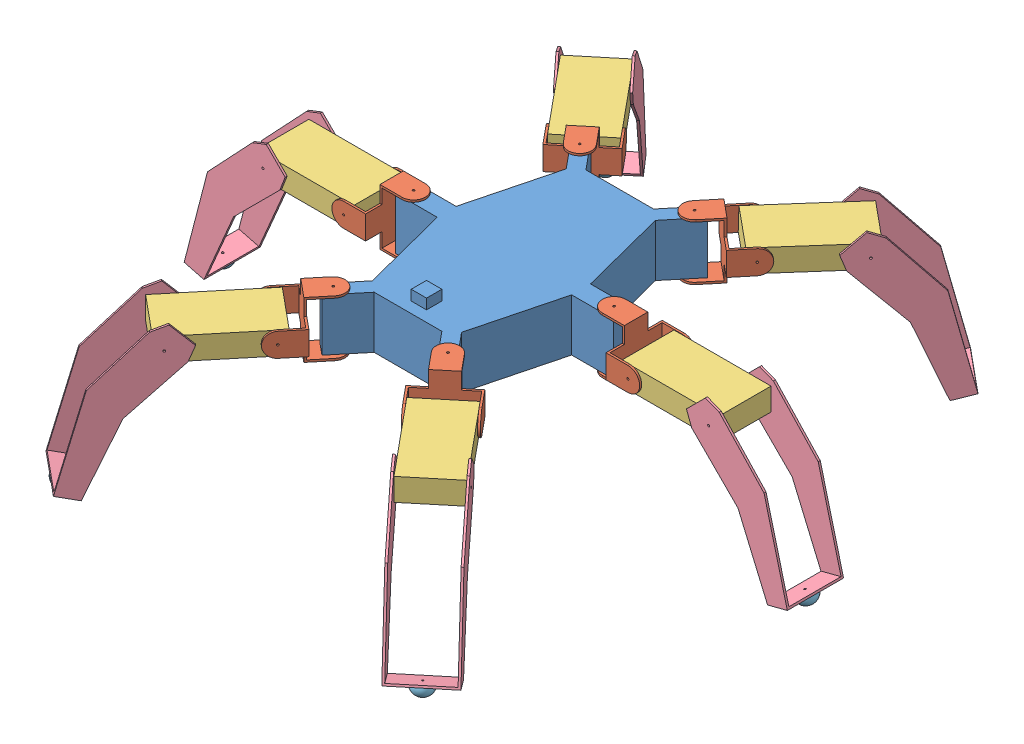
SolidWorks assembly Spider, configuration 默认. Lengths in mm.
Overall size (658.1 217.67 632.08).
25 component instances, 5 part files, 25 mates.
Components (placement in the parent):
- body-1: body [默认] at origin size (213.14 61 263.08)
- joint1-1: joint1 [默认] at (-68.5521 25.5 135.6395) x (0.770073 0 0.637956) z (-0.637956 0 0.770073) size (55 55 64)
- joint1-2: joint1 [默认] at (68.5521 25.5 135.6395) x (0.770073 0 -0.637956) z (0.637956 0 0.770073) size (55 55 64)
- joint1-3: joint1 [默认] at (117.5676 25.5 0) x (0 0 -1) z (1 0 0) size (55 55 64)
- joint1-5: joint1 [默认] at (68.5521 25.5 -135.6395) x (-0.770073 0 -0.637956) z (0.637956 0 -0.770073) size (55 55 64)
- joint1-6: joint1 [默认] at (-68.5521 25.5 -135.6395) x (-0.770073 0 0.637956) z (-0.637956 0 -0.770073) size (55 55 64)
- joint1-7: joint1 [默认] at (-117.5676 25.5 0) x (0 0 1) z (-1 0 0) size (55 55 64)
- joint2-1: joint2 [默认] at (107.3085 13.6422 -182.4222) x (0.770073 0 0.637956) z (-0.637804 0.021781 0.76989) size (51 22 95)
- joint2-2: joint2 [默认] at (-107.4674 14.5 -182.614) x (0.770073 0 -0.637956) z (0.637956 0 0.770073) size (51 22 95)
- joint2-3: joint2 [默认] at (-178.5676 14.5 0) x (0 0 1) z (-1 0 0) size (51 22 95)
- joint2-4: joint2 [默认] at (-107.4674 14.5 182.614) x (0.770073 0 0.637956) z (-0.637956 0 0.770073) size (51 22 95)
- joint2-5: joint2 [默认] at (107.4674 14.5 182.614) x (0.770073 0 -0.637956) z (0.637956 0 0.770073) size (51 22 95)
- joint2-6: joint2 [默认] at (178.5676 14.5 0) x (0 0 1) z (-1 0 0) size (51 22 95)
- joint3-1: joint3 [默认] at (123.6571 15.2329 199.0214) x (-0.451103 0.707107 -0.544524) z (-0.451103 -0.707107 -0.544524) size (155.7 55 65.29)
- joint3-14: joint3 [默认] at (201.5308 15.2329 -2) x (-0.707107 0.707107 0) z (-0.707107 -0.707107 0) size (155.7 55 65.29)
- joint3-15: joint3 [默认] at (120.4246 13.8748 -201.3896) x (-0.44117 0.722341 0.532534) z (-0.460822 -0.691537 0.556255) size (155.7 55 65.29)
- joint3-16: joint3 [默认] at (-123.6571 15.2329 -199.0214) x (0.451103 0.707107 0.544524) z (0.451103 -0.707107 0.544524) size (155.7 55 65.29)
- joint3-17: joint3 [默认] at (-201.5308 15.2329 2) x (0.707107 0.707107 0) z (0.707107 -0.707107 0) size (155.7 55 65.29)
- joint3-18: joint3 [默认] at (-120.5768 15.2329 201.5732) x (0.451103 0.707107 -0.544524) z (0.451103 -0.707107 -0.544524) size (155.7 55 65.29)
- joint4-1: joint4 [默认] at (285.3968 -95.1638 0) x (-0.784328 -0.203323 -0.586079) z (-0.567327 -0.147069 0.810254) size (20 9.95 20)
- joint4-5: joint4 [默认] at (173.9208 -98.3224 -262.8296) x (-0.753819 0.005921 -0.657056) z (-0.64052 -0.229717 0.732778) size (20 9.95 20)
- joint4-6: joint4 [默认] at (-175.6197 -95.1638 -264.8802) x (0.948773 -0.09687 -0.300744) z (-0.272402 0.231486 -0.933923) size (20 9.95 20)
- joint4-7: joint4 [默认] at (-285.3968 -95.1638 0) x (-0.814439 0.211129 -0.540475) z (-0.523181 0.135625 0.84136) size (20 9.95 20)
- joint4-8: joint4 [默认] at (175.6197 -95.1638 264.8802) x (-0.919522 -0.217431 -0.327418) z (-0.358958 0.125273 0.924909) size (20 9.95 20)
- joint4-9: joint4 [默认] at (-175.6197 -95.1638 264.8802) x (-0.835669 0.028709 -0.548483) z (-0.525386 0.24929 0.813526) size (20 9.95 20)
Mates (geometry in assembly coordinates):
- 重合1: coincident anti-aligned: circle of body-1; circle of joint1-1
- 重合3: coincident aligned: circle of body-1; circle of joint1-2
- 重合6: coincident aligned: circle of body-1; circle of joint1-3
- 重合7: coincident anti-aligned: circle of body-1; circle of joint1-5
- 重合9: coincident aligned: circle of body-1; circle of joint1-6
- 重合10: coincident anti-aligned: circle of body-1; circle of joint1-7
- 重合12: coincident aligned: circle of joint1-5; circle of joint2-1
- 重合13: coincident anti-aligned: circle of joint1-6; circle of joint2-2
- 重合14: coincident aligned: circle of joint1-7; circle of joint2-3
- 重合15: coincident aligned: circle of joint1-1; circle of joint2-4
- 重合16: coincident aligned: circle of joint1-2; circle of joint2-5
- 重合17: coincident anti-aligned: circle of joint1-3; circle of joint2-6
- 重合18: coincident aligned: circle of joint2-5; circle of joint3-1
- 重合24: coincident anti-aligned: circle of joint2-6; circle of joint3-14
- 重合25: coincident anti-aligned: circle of joint2-1; circle of joint3-15
- 重合26: coincident anti-aligned: circle of joint2-2; circle of joint3-16
- 重合27: coincident aligned: circle of joint2-3; circle of joint3-17
- 重合28: coincident aligned: circle of joint2-4; circle of joint3-18
- 重合30: coincident anti-aligned: circle of joint3-14; circle of joint4-1
- 重合33: coincident anti-aligned: circle of joint3-15; circle of joint4-5
- 重合34: coincident anti-aligned: circle of joint3-16; circle of joint4-6
- 重合35: coincident anti-aligned: circle of joint3-17; circle of joint4-7
- 重合36: coincident anti-aligned: circle of joint3-1; circle of joint4-8
- 重合37: coincident anti-aligned: circle of joint3-18; circle of joint4-9
- 角度8: planar angle = 2.356194 rad anti-aligned: plane of joint2-1 through (107.3085 13.6422 -182.4222) normal (-0.013896 -0.999763 0.016773); plane of joint3-15 through (102.3279 13.8748 -216.3816) normal (-0.460822 -0.691537 0.556255)
